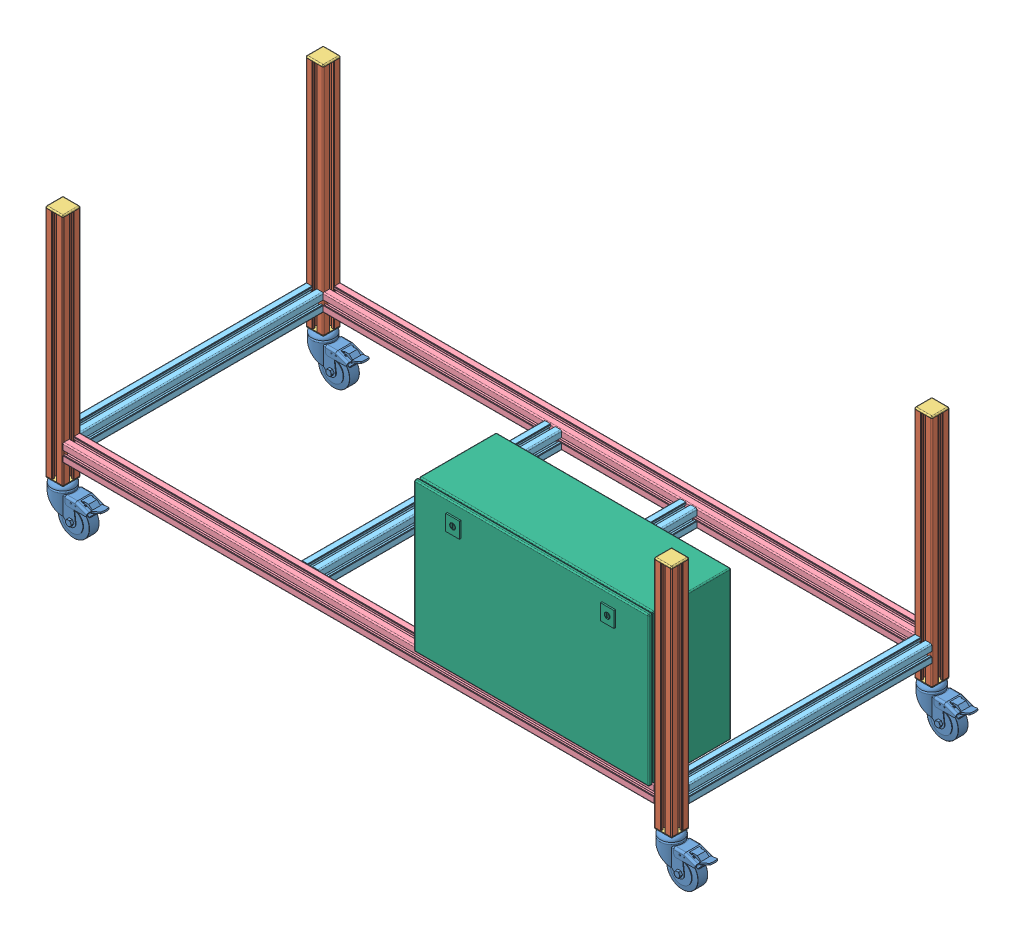
SolidWorks assembly Base, configuration Default. Lengths in mm.
Overall size (1693.5 709 733).
28 component instances, 7 part files, 40 mates.
Components (placement in the parent):
- Perna-1: Perna [Default] at origin size (138.5 705 57)
  - Roda-1: Roda [Default] at origin size (138.5 148 57)
  - Perfil45_593-1: Perfil45_593 [Default] at (0 4 0) x (1 0 0) z (0 -1 0) size (45 45 593)
  - Tampa-2: Tampa [Default] at (0 4 0) x (1 0 0) z (0 -1 0) size (45.64 46.27 5.14)
- Perfil45_1510-1: Perfil45_1510 [Default] at (22.5 76.5 0) x (0 0 1) z (-1 0 0) size (45 45 1510)
- Perna-2: Perna [Default] at (1555 0 0) size (138.5 705 57)
  - Roda-1: Roda [Default] at origin size (138.5 148 57)
  - Perfil45_593-1: Perfil45_593 [Default] at (0 4 0) x (1 0 0) z (0 -1 0) size (45 45 593)
  - Tampa-2: Tampa [Default] at (0 4 0) x (1 0 0) z (0 -1 0) size (45.64 46.27 5.14)
- Perna-3: Perna [Default] at (1555 0 -665) size (138.5 705 57)
  - Roda-1: Roda [Default] at origin size (138.5 148 57)
  - Perfil45_593-1: Perfil45_593 [Default] at (0 4 0) x (1 0 0) z (0 -1 0) size (45 45 593)
  - Tampa-2: Tampa [Default] at (0 4 0) x (1 0 0) z (0 -1 0) size (45.64 46.27 5.14)
- Perna-4: Perna [Default] at (0 0 -665) size (138.5 705 57)
  - Roda-1: Roda [Default] at origin size (138.5 148 57)
  - Perfil45_593-1: Perfil45_593 [Default] at (0 4 0) x (1 0 0) z (0 -1 0) size (45 45 593)
  - Tampa-2: Tampa [Default] at (0 4 0) x (1 0 0) z (0 -1 0) size (45.64 46.27 5.14)
- Perfil45_620-1: Perfil45_620 [Default] at (0 76.5 -22.5) size (45 45 620)
- Perfil45_620-2: Perfil45_620 [Default] at (1555 76.5 -22.5) size (45 45 620)
- Perfil45_1510-2: Perfil45_1510 [Default] at (22.5 76.5 -665.0001) x (0 0 1) z (-1 0 0) size (45 45 1510)
- Tampa-2: Tampa [Default] at (0 597 0) x (1 0 0) z (0 1 0) size (45.64 46.27 5.14)
- Tampa-3: Tampa [Default] at (1554.9999 597 0) x (-1 0 0) z (0 1 0) size (45.64 46.27 5.14)
- Tampa-4: Tampa [Default] at (1554.9999 597 -665) x (0 0 -1) z (0 1 0) size (45.64 46.27 5.14)
- Tampa-5: Tampa [Default] at (0 597 -665) x (0 0 -1) z (0 1 0) size (45.64 46.27 5.14)
- Quadro-1: Quadro [Default] at (932.5 99 -174.5) size (600 380 214)
- Perfil45_620-3: Perfil45_620 [Default] at (609 76.5 -22.4999) size (45 45 620)
- Perfil45_620-4: Perfil45_620 [Default] at (955 76.5 -22.5001) size (45 45 620)
- Seccionador-1: Seccionador [Default] at (997.6 387.2529 -76) x (0 -1 0) z (0 0 -1) size (63 46.61 63)
Mates (geometry in assembly coordinates):
- Coincident1: coincident anti-aligned: plane of Perna-1/Perfil45_593-1 through (22.5 597 -6.3) normal (1 0 0); plane of Perfil45_1510-1 through (22.5 76.487 7.7309) normal (-1 0 0)
- Coincident2: coincident aligned: plane of Perna-1/Perfil45_593-1 through (19.5 597 22.5) normal (0 0 1); plane of Perfil45_1510-1 through (1532.5 70.2 22.5) normal (0 0 1)
- Distance2: distance = 50 mm: plane of Perfil45_1510-1 through (1532.5 54 19.5) normal (0 -1 0); line of Perna-1/Perfil45_593-1 through (19.5 4 22.5) axis (-1 0 0)
- Coincident5: coincident anti-aligned: plane of Perfil45_1510-1 through (1532.5 76.487 7.7309) normal (1 0 0); plane of Perna-2/Perfil45_593-1 through (1532.5 597 6.3) normal (-1 0 0)
- Coincident6: coincident aligned: plane of Perfil45_1510-1 through (1532.5 70.2 22.5) normal (0 0 1); plane of Perna-2/Perfil45_593-1 through (1535.5 597 22.5) normal (0 0 1)
- Distance3: distance = 50 mm: plane of Perfil45_1510-1 through (1532.5 54 19.5) normal (0 -1 0); line of Perna-2/Perfil45_593-1 through (1548.6242 4 22.5) axis (-1 0 0)
- Coincident8: coincident anti-aligned: plane of Perna-1/Perfil45_593-1 through (-19.5 597 -22.5) normal (0 0 -1); plane of Perfil45_620-1 through (7.7309 76.487 -22.5) normal (0 0 1)
- Coincident9: coincident aligned: plane of Perna-1/Perfil45_593-1 through (22.5 597 -6.3) normal (1 0 0); plane of Perfil45_620-1 through (22.5 82.8 -642.5) normal (1 0 0)
- Distance4: distance = 50 mm: plane of Perfil45_620-1 through (19.5 54 -642.5) normal (0 -1 0); line of Perna-1/Perfil45_593-1 through (6.3757 4 -22.5) axis (1 0 0)
- Coincident11: coincident anti-aligned: plane of Perna-4/Perfil45_593-1 through (-19.5 597 -642.5) normal (0 0 1); plane of Perfil45_620-1 through (7.7309 76.487 -642.5) normal (0 0 -1)
- Coincident12: coincident aligned: plane of Perna-4/Perfil45_593-1 through (22.5 597 -658.7) normal (1 0 0); plane of Perfil45_620-1 through (22.5 82.8 -642.5) normal (1 0 0)
- Distance5: distance = 50 mm: plane of Perfil45_620-1 through (19.5 54 -642.5) normal (0 -1 0); line of Perna-4/Tampa-2 through (22.5 4 -684.5) axis (0 0 1)
- Coincident14: coincident anti-aligned: plane of Perna-2/Perfil45_593-1 through (1574.4999 597 -22.5) normal (0 0 -1); plane of Perfil45_620-2 through (1562.7309 76.487 -22.5) normal (0 0 1)
- Coincident15: coincident aligned: plane of Perna-2/Perfil45_593-1 through (1577.4999 597 -6.3) normal (1 0 0); plane of Perfil45_620-2 through (1577.4999 82.8 -642.5) normal (1 0 0)
- Distance6: distance = 50 mm: plane of Perfil45_620-2 through (1574.4999 54 -642.5) normal (0 -1 0); line of Perna-2/Perfil45_593-1 through (1561.3757 4 -22.5) axis (1 0 0)
- Coincident17: coincident anti-aligned: plane of Perna-3/Perfil45_593-1 through (1574.4999 597 -642.5) normal (0 0 1); plane of Perfil45_620-2 through (1562.7309 76.487 -642.5) normal (0 0 -1)
- Coincident18: coincident aligned: plane of Perna-3/Perfil45_593-1 through (1577.4999 597 -658.7) normal (1 0 0); plane of Perfil45_620-2 through (1577.4999 82.8 -642.5) normal (1 0 0)
- Distance7: distance = 50 mm: line of Perfil45_620-2 through (1561.3757 54 -642.5) axis (1 0 0); line of Perna-3/Perfil45_593-1 through (1574.4999 4 -642.5) axis (-1 0 0)
- Coincident20: coincident anti-aligned: plane of Perna-4/Perfil45_593-1 through (22.5 597 -658.7) normal (1 0 0); plane of Perfil45_1510-2 through (22.5 76.487 -657.2692) normal (-1 0 0)
- Coincident21: coincident aligned: plane of Perna-4/Perfil45_593-1 through (19.5 597 -687.5) normal (0 0 -1); plane of Perfil45_1510-2 through (1532.5 70.2 -687.5) normal (0 0 -1)
- Distance8: distance = 50 mm: line of Perfil45_1510-2 through (22.5 54 -684.5) axis (0 0 1); line of Perna-4/Perfil45_593-1 through (6.3757 4 -687.5) axis (1 0 0)
- Coincident22: coincident anti-aligned: plane of Perna-1/Perfil45_593-1 through (7.7309 597 -0.013) normal (0 1 0); plane of Tampa-2 through (0 597 0) normal (0 -1 0)
- Coincident23: coincident aligned: plane of Perna-1/Perfil45_593-1 through (19.5 597 22.5) normal (0 0 1); plane of Tampa-2 through (-22.5 597 22.5) normal (0 0 1)
- Coincident24: coincident aligned: plane of Perna-1/Perfil45_593-1 through (22.5 597 6.3) normal (1 0 0); plane of Tampa-2 through (22.5 597 22.5) normal (1 0 0)
- Coincident25: coincident anti-aligned: plane of Perna-2/Perfil45_593-1 through (1562.7309 597 -0.013) normal (0 1 0); plane of Tampa-3 through (1554.9999 597 0) normal (0 -1 0)
- Coincident26: coincident aligned: plane of Perna-2/Perfil45_593-1 through (1577.4999 597 6.3) normal (1 0 0); plane of Tampa-3 through (1577.4999 597 22.5) normal (1 0 0)
- Coincident27: coincident aligned: plane of Perna-2/Perfil45_593-1 through (1574.4999 597 -22.5) normal (0 0 -1); plane of Tampa-3 through (1577.4999 597 -22.5) normal (0 0 -1)
- Coincident28: coincident anti-aligned: plane of Perna-3/Perfil45_593-1 through (1562.7309 597 -665.013) normal (0 1 0); plane of Tampa-4 through (1554.9999 597 -665) normal (0 -1 0)
- Coincident29: coincident aligned: plane of Perna-3/Perfil45_593-1 through (1577.4999 597 -671.3) normal (1 0 0); plane of Tampa-4 through (1577.4999 597 -642.5) normal (1 0 0)
- Coincident30: coincident aligned: plane of Perna-3/Perfil45_593-1 through (1574.4999 597 -687.5) normal (0 0 -1); plane of Tampa-4 through (1577.4999 597 -687.5) normal (0 0 -1)
- Coincident31: coincident anti-aligned: plane of Perna-4/Perfil45_593-1 through (7.7309 597 -665.013) normal (0 1 0); plane of Tampa-5 through (0 597 -665) normal (0 -1 0)
- Coincident32: coincident aligned: plane of Perna-4/Perfil45_593-1 through (19.5 597 -687.5) normal (0 0 -1); plane of Tampa-5 through (22.5 597 -687.5) normal (0 0 -1)
- Coincident33: coincident aligned: plane of Perna-4/Perfil45_593-1 through (-22.5 597 -671.3) normal (-1 0 0); plane of Tampa-5 through (-22.5 597 -687.5) normal (-1 0 0)
- Coincident98: coincident aligned: plane of Perfil45_1510-1 through (1532.5 82.8 22.5) normal (0 0 1); plane of Quadro-1 through (932.5 99 22.5) normal (0 0 1)
- Coincident99: coincident anti-aligned: plane of Perna-2/Perfil45_593-1 through (1532.5 597 -6.3) normal (-1 0 0); plane of Quadro-1 through (1532.5 99 35.5) normal (1 0 0)
- Coincident100: coincident anti-aligned: plane of Perfil45_1510-1 through (1532.5 99 -19.4999) normal (0 1 0); plane of Quadro-1 through (932.5 99 35.5) normal (0 -1 0)
- Coincident101: coincident aligned: plane of Perfil45_1510-2 through (1532.5 99 -645.5001) normal (0 1 0); plane of Perfil45_620-3 through (589.5 99 -642.4999) normal (0 1 0)
- Coincident102: coincident anti-aligned: plane of Perfil45_1510-1 through (1532.5 82.8 -22.4999) normal (0 0 -1); plane of Perfil45_620-3 through (616.7309 76.487 -22.4999) normal (0 0 1)
- Coincident1141: coincident anti-aligned: plane of Perfil45_1510-2 through (1532.5 70.2 -642.5001) normal (0 0 1); plane of Perfil45_620-4 through (962.7309 76.487 -642.5001) normal (0 0 -1)
- Coincident1142: coincident aligned: plane of Perfil45_1510-2 through (1532.5 99 -645.5001) normal (0 1 0); plane of Perfil45_620-4 through (974.4999 99 -642.5001) normal (0 1 0)
